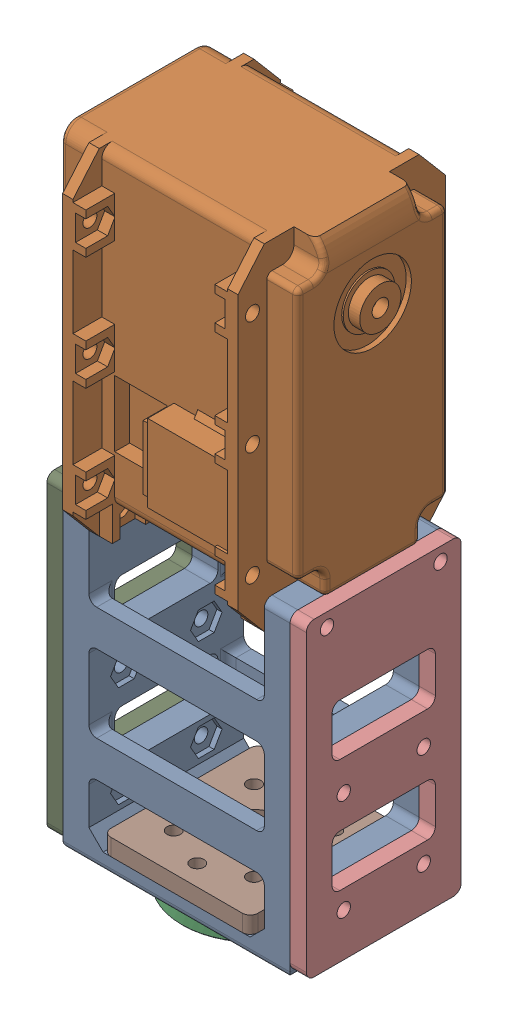
SolidWorks assembly Link4, configuration Default. Lengths in mm.
Overall size (51.55 125.32 40.2).
6 component instances, 5 part files, 15 mates.
Components (placement in the parent):
- HN07-N101-short-ex-ex_v2-2: HN07-N101-short-ex-ex_v2 [Default] at (-78.2986 21.7617 89.9609) size (44 61.3 30)
- EX-106+-1: EX-106+ [Default] at (-56.2986 128.2617 74.9609) x (0 0 1) z (-1 0 0) size (40.2 65.92 50.9)
- HN05-N101-1: HN05-N101 [Default] at (-56.2986 19.2617 74.9609) size (28 5.3 28)
- HN07-N101-short-ex-ex_horn_reinforcement-1: HN07-N101-short-ex-ex_horn_reinforcement [Default] at (-56.2986 25.1117 74.9609) x (0 0 1) z (1 0 0) size (30 3.25 28.5)
- HN07-N101-short-ex-ex_side_reinforcement-1: HN07-N101-short-ex-ex_side_reinforcement [Default] at (-81.4486 53.0367 74.9609) x (0 0 1) z (0 -1 0) size (30 3.15 60.05)
- HN07-N101-short-ex-ex_side_reinforcement-2: HN07-N101-short-ex-ex_side_reinforcement [Default] at (-34.2986 53.0367 74.9609) x (0 0 1) z (0 -1 0) size (30 3.15 60.05)
Mates (geometry in assembly coordinates):
- Concentric3: concentric aligned: circle of HN07-N101-short-ex-ex-1; circle of HN05-N101-1
- Concentric4: concentric anti-aligned: circle of HN07-N101-short-ex-ex-1; circle of HN05-N101-1
- Coincident1: coincident anti-aligned: plane of HN07-N101-short-ex-ex_v2-2 through (-78.2986 21.7617 89.9609) normal (0 -1 0); plane of HN05-N101-1 through (-56.2986 21.7617 74.9609) normal (0 1 0)
- Concentric5: concentric aligned: circle of HN07-N101-short-ex-ex-1; circle of EX-106+-1
- Concentric6: concentric aligned: circle of HN07-N101-short-ex-ex-1; circle of EX-106+-1
- Coincident2: coincident anti-aligned: plane of HN07-N101-short-ex-ex_v2-2 through (-39.2986 83.0617 59.9609) normal (-1 0 0); plane of EX-106+-1 through (-39.2986 128.2617 74.9609) normal (1 0 0)
- Concentric7: concentric anti-aligned: circle of HN07-N101-short-ex-ex_v2-2; circle of HN07-N101-short-ex-ex_side_reinforcement-1
- Concentric8: concentric anti-aligned: circle of HN07-N101-short-ex-ex_v2-2; circle of HN07-N101-short-ex-ex_side_reinforcement-1
- Coincident5: coincident anti-aligned: plane of HN07-N101-short-ex-ex_v2-2 through (-78.2986 76.2617 89.9609) normal (-1 0 0); plane of HN07-N101-short-ex-ex_side_reinforcement-1 through (-78.2986 53.0367 74.9609) normal (1 0 0)
- Concentric10: concentric anti-aligned: circle of HN07-N101-short-ex-ex_v2-2; circle of HN07-N101-short-ex-ex_side_reinforcement-2
- Concentric11: concentric anti-aligned: circle of HN07-N101-short-ex-ex_v2-2; circle of HN07-N101-short-ex-ex_side_reinforcement-2
- Coincident9: coincident anti-aligned: plane of HN07-N101-short-ex-ex_v2-2 through (-34.2986 76.2617 89.9609) normal (1 0 0); plane of HN07-N101-short-ex-ex_side_reinforcement-2 through (-34.2986 53.0367 74.9609) normal (-1 0 0)
- Concentric15: concentric aligned: circle of HN07-N101-short-ex-ex_v2-2; circle of HN07-N101-short-ex-ex_horn_reinforcement-1
- Concentric16: concentric aligned: circle of HN07-N101-short-ex-ex_v2-2; circle of HN07-N101-short-ex-ex_horn_reinforcement-1
- Coincident17: coincident anti-aligned: plane of HN07-N101-short-ex-ex_v2-2 through (-78.2986 25.0117 89.9609) normal (0 1 0); plane of HN07-N101-short-ex-ex_horn_reinforcement-1 through (-56.2986 25.0117 74.9609) normal (0 -1 0)
